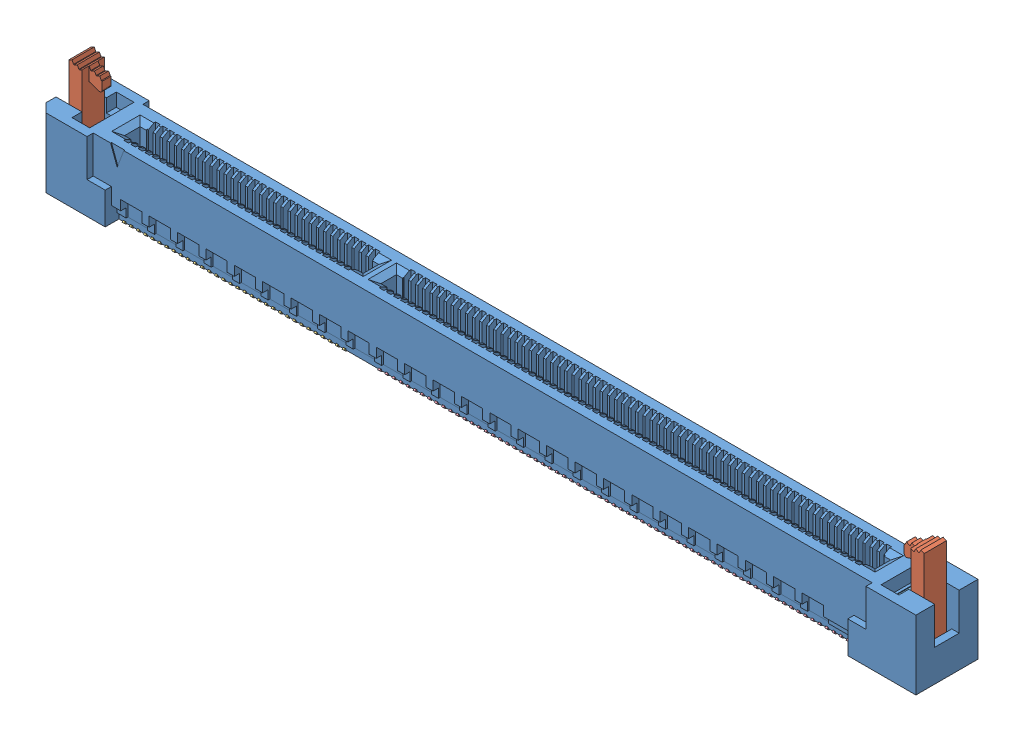
SolidWorks assembly HSEC8_1100_01_L_DV_BL, configuration Default. Lengths in mm.
Overall size (99.05 13.68 7).
7 component instances, 5 part files, 0 mates.
Components (placement in the parent):
- _HSEC8_1100_01_L_DV_BLter_2-1: _HSEC8_1100_01_L_DV_BLter_2 [Default] at origin size (99.05 7.8 7)
- _LTC_04_4-1: _LTC_04_4 [Default] at (-47.45 1.75 0) size (3.4 11.6 2.75)
- _LTC_04_4-2: _LTC_04_4 [Default] at (47.45 1.75 0) x (-1 0 0) z (0 0 -1) size (3.4 11.6 2.75)
- _C_188_02_Pin_32_01_7-1: _C_188_02_Pin_32_01_7 [Default] at (-41.2 -0.183 0) x (0 0 1) z (-1 0 0) size (4.26 5.75 25.38)
- _C_188_02_Pin_68_01_9-1: _C_188_02_Pin_68_01_9 [Default] at (-12.4 -0.183 0) x (0 0 1) z (-1 0 0) size (4.26 5.75 54.18)
- _WT_25_02_T_Latching_Option_BL_11-1: _WT_25_02_T_Latching_Option_BL_11 [Default] at (-45.05 6.245 0) x (0 0 -1) z (1 0 0) size (4.45 7.73 0.25)
- _WT_25_02_T_Latching_Option_BL_11-2: _WT_25_02_T_Latching_Option_BL_11 [Default] at (45.05 6.245 0) x (0 0 -1) z (1 0 0) size (4.45 7.73 0.25)
